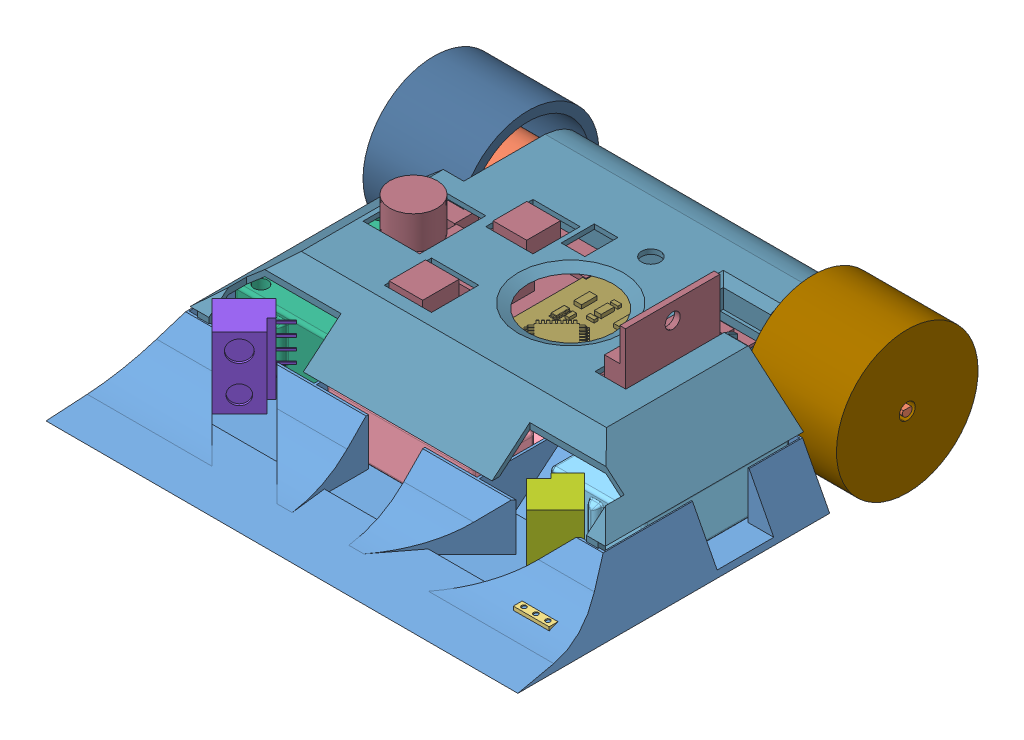
SolidWorks assembly Assem2, configuration Default. Lengths in mm.
Overall size (100.86 41.59 102.63).
19 component instances, 14 part files, 28 mates.
Components (placement in the parent):
- temel gövde2-1: temel gövde2 [Varsayılan] at (-38.1533 30.8628 -7.99) size (100 11 91.59)
- maxon-1: maxon [Varsayılan] at (-71.1082 42.8628 -21.9695) x (0 -0.012694 -0.999919) z (1 0 0) size (16 19 50.6)
- QTR_1A-1: QTR_1A [Varsayılan] at (-85.6036 35.8628 21.5129) x (0 0 -1) z (-1 0 0) size (12.6 2 7.6)
- maxon-2: maxon [Varsayılan] at (13.228 42.8628 -21.9695) x (0 0.031043 0.999518) z (-1 0 0) size (16 19 50.6)
- QTR_1A-2: QTR_1A [Varsayılan] at (-1.3414 35.8628 24.0356) x (0 0 -1) z (-1 0 0) size (12.6 2 7.6)
- omron4-1: omron4 [Default] at (-28.2523 44.6628 26.2459) x (1 0 0) z (0 0 -1) size (37.72 10.8 25.16)
- omron4 - Copy-1: omron4 - Copy [Default] at (5.2477 44.6628 12.3175) x (0 0 -1) z (-1 0 0) size (37.72 10.8 25.16)
- omron5-1: omron5 [Default] at (-61.7523 33.8628 12.3175) x (0 0 -1) z (1 0 0) size (37.72 10.8 25.16)
- sharp - Copy-1: sharp - Copy [Default] at (-9.3696 42.0847 28.1157) x (-0.707107 0 -0.707107) z (0 -1 0) size (12.7 8.7 15)
- sharp - Copy - Copy-1: sharp - Copy - Copy [Default] at (-46.5757 40.6409 28.8163) x (0.707107 0 -0.707107) z (0 1 0) size (12.7 8.7 15)
- tekerlek-1: tekerlek [Default] at (1.228 42.8628 -21.9695) x (1 0 0) z (0 0.031815 0.999494) size (20 30 30)
- tekerlek2-1: tekerlek2 [Default] at (-59.1082 42.8628 -21.9695) x (-1 0 0) z (0 -0.924225 -0.381849) size (20 30 30)
- batt-1: batt [Default] at (-30.9003 35.2036 -3.2517) size (42 14 8)
- batt-2: batt [Default] at (-30.872 35.2036 -12.1611) size (42 14 8)
- batt-3: batt [Default] at (-30.7749 35.2036 5.6612) size (42 14 8)
- Arduino_pro_mini-1: Arduino_pro_mini [Varsayılan] at (-38.5038 24.8319 -8.1735) x (0 0 1) z (-1 0 0) size (33 1.8 17.8)
  - Main-1: Main [Varsayılan] at (-1.8184 24.0309 -7.5805) size (33 1.8 17.8)
- kart-2: kart [Default] at (-51.0788 47.8628 1.7691) x (-1 0 0) z (0 0 -1) size (57.36 17 39)
- kapak2-1: kapak2 [Default] at (-13.5647 45.0243 28.9059) size (88 21.55 69)
Mates (geometry in assembly coordinates):
- Concentric1: concentric anti-aligned: cylinder of temel gövde2-1 through (-100.2523 42.8628 -21.9695) axis (1 0 0) radius 8.05; cylinder of maxon-1 through (-29.5082 42.8628 -21.9695) axis (-1 0 0) radius 8
- Coincident1: coincident anti-aligned: plane of temel gövde2-1 through (-38.1533 35.8628 -7.99) normal (0 -1 0); plane of QTR_1A-1 through (-85.6036 35.8628 21.5129) normal (0 1 0)
- Parallel2: parallel anti-aligned: line of temel gövde2-1 through (-75.2523 36.0192 46.0694) axis (1 0 0); line of QTR_1A-1 through (-68.4194 35.8628 46.0129) axis (-1 0 0)
- Concentric2: concentric aligned: cylinder of temel gövde2-1 through (-100.2523 42.8628 -21.9695) axis (1 0 0) radius 8.05; cylinder of maxon-2 through (-28.372 42.8628 -21.9695) axis (1 0 0) radius 8
- Coincident4: coincident anti-aligned: plane of temel gövde2-1 through (-38.1533 35.8628 -7.99) normal (0 -1 0); plane of QTR_1A-2 through (-1.3414 35.8628 24.0356) normal (0 1 0)
- Parallel3: parallel aligned: line of temel gövde2-1 through (19.7477 32.8628 46.0694) axis (-1 0 0); line of QTR_1A-2 through (15.8428 34.8628 48.5356) axis (-1 0 0)
- Concentric3: concentric anti-aligned: circle of temel gövde2-1; circle of omron4-1
- Concentric4: concentric anti-aligned: circle of temel gövde2-1; circle of omron4-1
- Coincident6: coincident anti-aligned: plane of temel gövde2-1 through (-62.5365 33.8628 27.7852) normal (0 1 0); plane of omron4-1 through (-28.2523 33.8628 26.2459) normal (0 -1 0)
- Concentric5: concentric anti-aligned: circle of temel gövde2-1; circle of omron4 - Copy-1
- Concentric6: concentric anti-aligned: circle of temel gövde2-1; circle of omron4 - Copy-1
- Coincident7: coincident anti-aligned: plane of temel gövde2-1 through (-62.5365 33.8628 27.7852) normal (0 1 0); plane of omron4 - Copy-1 through (5.2477 33.8628 12.3175) normal (0 -1 0)
- Concentric7: concentric aligned: circle of temel gövde2-1; circle of omron5-1
- Concentric8: concentric aligned: circle of temel gövde2-1; circle of omron5-1
- Coincident8: coincident anti-aligned: plane of temel gövde2-1 through (-62.5365 33.8628 27.7852) normal (0 1 0); plane of omron5-1 through (-61.7523 33.8628 12.3175) normal (0 -1 0)
- Coincident9: coincident anti-aligned: plane of temel gövde2-1 through (-62.5365 33.8628 27.7852) normal (0 1 0); plane of sharp - Copy - Copy-1 through (-63.5865 33.8628 40.5945) normal (0 -1 0)
- Coincident10: coincident anti-aligned: plane of temel gövde2-1 through (-69.4662 33.8628 34.7148) normal (0.707107 0 -0.707107); plane of sharp - Copy - Copy-1 through (-63.5865 33.8628 40.5945) normal (-0.707107 0 0.707107)
- Coincident11: coincident anti-aligned: plane of temel gövde2-1 through (-62.5365 33.8628 27.7852) normal (0 1 0); plane of sharp - Copy-1 through (7.6412 33.8628 39.8939) normal (0 -1 0)
- Coincident12: coincident anti-aligned: plane of temel gövde2-1 through (12.8909 33.8628 34.6441) normal (-0.707107 0 -0.707107); plane of sharp - Copy-1 through (7.6412 48.8628 39.8939) normal (0.707107 0 0.707107)
- Concentric9: concentric aligned: circle of maxon-2; circle of tekerlek-1
- Coincident13: coincident aligned: plane of maxon-2 through (21.228 42.8628 -21.9695) normal (1 0 0); plane of tekerlek-1 through (21.228 42.8628 -21.9695) normal (1 0 0)
- Coincident14: coincident aligned: plane of maxon-1 through (-79.1082 42.8628 -21.9695) normal (-1 0 0); plane of tekerlek2-1 through (-79.1082 42.8628 -21.9695) normal (-1 0 0)
- Concentric10: concentric aligned: circle of maxon-1; circle of tekerlek2-1
- Coincident15: coincident anti-aligned: plane of temel gövde2-1 through (-62.5365 33.8628 27.7852) normal (0 1 0); plane of batt-1 through (-50.3516 33.8628 4.7483) normal (0 -1 0)
- Coincident16: coincident anti-aligned: plane of temel gövde2-1 through (-62.5365 33.8628 27.7852) normal (0 1 0); plane of batt-2 through (-50.3233 33.8628 -4.1611) normal (0 -1 0)
- Coincident17: coincident anti-aligned: plane of temel gövde2-1 through (-62.5365 33.8628 27.7852) normal (0 1 0); plane of batt-3 through (-50.2263 33.8628 13.6612) normal (0 -1 0)
- Coincident18: coincident anti-aligned: plane of Arduino_pro_mini-1/Main-1 through (-30.9233 48.8628 -9.9919) normal (0 -1 0); plane of kart-2 through (-51.0788 48.8628 1.7691) normal (0 1 0)
- Coincident19: coincident anti-aligned: plane of batt-3 through (-50.2263 47.8628 13.6612) normal (0 1 0); plane of kart-2 through (-51.0788 47.8628 1.7691) normal (0 -1 0)
